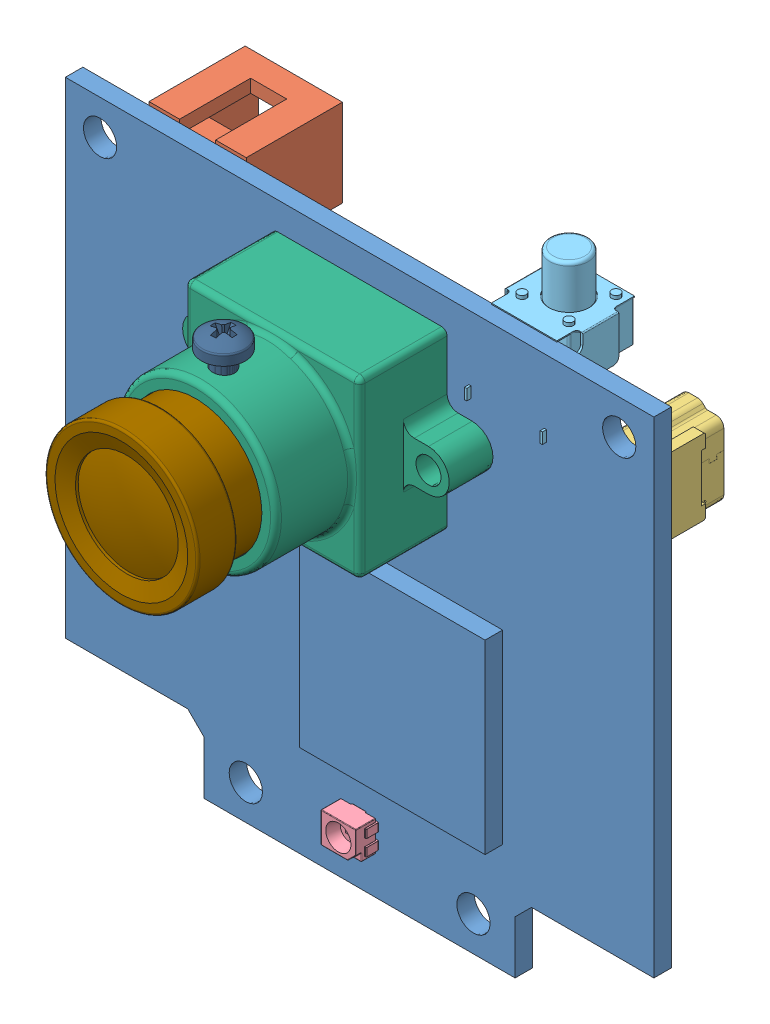
SolidWorks assembly Pixy(CMUcam5), configuration rev1.3. Lengths in mm.
Overall size (53.85 54.8 33.85).
10 component instances, 10 part files, 28 mates.
Components (placement in the parent):
- Pixy_board-1: Pixy_board [rev1.3] at origin size (53.85 50.8 3.2)
- header_2x5ways-1: header_2x5ways [Default] at (-18.024 -0.91 -1.4) x (0 1 0) z (0 0 -1) size (20.3 10 10.4)
- mini_usb_b_vertical_connector-1: mini_usb_b_vertical_connector [Défaut] at (20.324 -0.785 -9.4) x (0 -1 0) z (0 0 -1) size (7.7 4.7 9.8)
- RGB_led_CMS-1: RGB_led_CMS [STD] at (0 -35.26 1.6) x (1 0 0) z (0 -1 0) size (3.5 1.95 2.8)
- switch-FSMRA6JH-1: switch-FSMRA6JH [Défaut] at (13.549 10.54 -4.01) x (-1 0 0) z (0 0 -1) size (7.11 10.9 8.99)
- M12_lens_holder-1: M12_lens_holder [Défaut] at (0 0 1.6) size (24.4 16 15)
- header3x2-1: header3x2 [Défaut] at (-14.924 -22.91 -2) x (1 0 0) z (0 1 0) size (8 10.45 7.62)
- header_MTA-100_2pins-1: header_MTA-100_2pins [Défaut] at (-14.924 -30.56 -2.54) x (1 0 0) z (0 0 -1) size (5.08 5.84 10.03)
- pixy_lens-1: pixy_lens [Défaut] at (0 0 6.4) x (0.989146 0.146935 0) z (0.146935 -0.989146 0) size (14 17 14)
- pan head cross recess screw_iso-1: pan head cross recess screw_iso [ISO 7045 - M2 x 4 - Z --- 4C] at (0 10.3386 14.06) x (0 -1 0) z (0.040708 0 0.999171) size (5.57 4 4)
Mates (geometry in assembly coordinates):
- Coincident1: coincident aligned: plane of Pixy_board-1 through (0 0 0) normal (0 0 1); plane of header_2x5ways-1 through (-22.724 -11.06 0) normal (0 0 1)
- Parallel2: parallel anti-aligned: plane of header_2x5ways-1 through (-22.474 -11.06 -1.6) normal (-1 0 0); plane of Pixy_board-1 through (0 0 0) normal (1 0 0)
- Coincident5: coincident: point of Pixy_board-1; plane of header_2x5ways-1
- Coincident6: coincident: point of Pixy_board-1; plane of header_2x5ways-1
- Coincident7: coincident anti-aligned: plane of mini_usb_b_vertical_connector-1 through (20.324 -0.785 0) normal (0 0 -1); plane of assembly through (0 0 0) normal (0 0 1)
- Coincident8: coincident: point of Pixy_board-1; plane of mini_usb_b_vertical_connector-1
- Coincident9: coincident: point of Pixy_board-1; plane of mini_usb_b_vertical_connector-1
- Parallel3: parallel anti-aligned: plane of mini_usb_b_vertical_connector-1; plane of assembly through (0 0 0) normal (1 0 0)
- Coincident11: coincident aligned: plane of Pixy_board-1 through (0 0 1.6) normal (0 0 1); plane of RGB_led_CMS-1 through (0 -35.26 1.6) normal (0 0 1)
- Coincident12: coincident: point of Pixy_board-1; plane of RGB_led_CMS-1
- Coincident13: coincident: point of Pixy_board-1; plane of RGB_led_CMS-1 through (0 -35.26 1.6) normal (0 -1 0)
- Parallel4: parallel aligned: plane of Pixy_board-1 through (0 0 0) normal (1 0 0); plane of RGB_led_CMS-1
- Coincident15: coincident anti-aligned: plane of Pixy_board-1 through (0 0 0) normal (0 0 1); plane of switch-FSMRA6JH-1 through (13.549 10.54 0) normal (0 0 -1)
- Coincident16: coincident aligned: plane of Pixy_board-1 through (26.924 10.54 75.6287) normal (0 1 0); plane of switch-FSMRA6JH-1
- Coincident17: coincident: point of Pixy_board-1; plane of switch-FSMRA6JH-1 through (13.549 10.54 -4.01) normal (-1 0 0)
- Coincident21: coincident aligned: plane of Pixy_board-1 through (0 0 1.6) normal (0 0 1); plane of M12_lens_holder-1 through (0 0 1.6) normal (0 0 1)
- Coincident22: coincident aligned: plane of Pixy_board-1 through (0 0 0) normal (0 1 0); plane of M12_lens_holder-1 through (0 0 1.6) normal (0 1 0)
- Coincident23: coincident aligned: plane of M12_lens_holder-1 through (0 0 1.6) normal (1 0 0); plane of assembly through (0 0 0) normal (1 0 0)
- Coincident24: coincident anti-aligned: plane of Pixy_board-1 through (0 0 0) normal (0 0 1); plane of header3x2-1 through (-14.924 -22.91 0) normal (0 0 -1)
- Coincident25: coincident: point of Pixy_board-1; plane of header3x2-1 through (-14.924 -22.91 -2) normal (0 1 0)
- Coincident27: coincident: point of Pixy_board-1; plane of header3x2-1
- Coincident28: coincident anti-aligned: plane of Pixy_board-1 through (0 0 0) normal (0 0 1); plane of header_MTA-100_2pins-1 through (-14.924 -30.56 0) normal (0 0 -1)
- Coincident29: coincident: point of Pixy_board-1; plane of header_MTA-100_2pins-1
- Coincident30: coincident: point of Pixy_board-1; plane of header_MTA-100_2pins-1 through (-14.924 -30.56 -2.54) normal (0 -1 0)
- Parallel5: parallel aligned: plane of Pixy_board-1 through (0 0 0) normal (1 0 0); plane of header_MTA-100_2pins-1
- Concentric1: concentric anti-aligned: cylinder of M12_lens_holder-1 through (0 0 16.6) axis (0 0 -1) radius 6.05; cylinder of pixy_lens-1 through (0 0 27.0365) axis (0 0 1) radius 6
- Distance1: distance = 23.4 mm anti-aligned: plane of pixy_lens-1 through (1.0285 -6.924 23.4) normal (0 0 1); plane of Pixy_board-1 through (0 0 0) normal (0 0 -1)
- Concentric4: concentric anti-aligned: cylinder of M12_lens_holder-1 through (0 8 14.06) axis (0 -1 0) radius 1; cylinder of pan head cross recess screw_iso-1 through (0 35.7386 14.06) axis (0 1 0) radius 1
